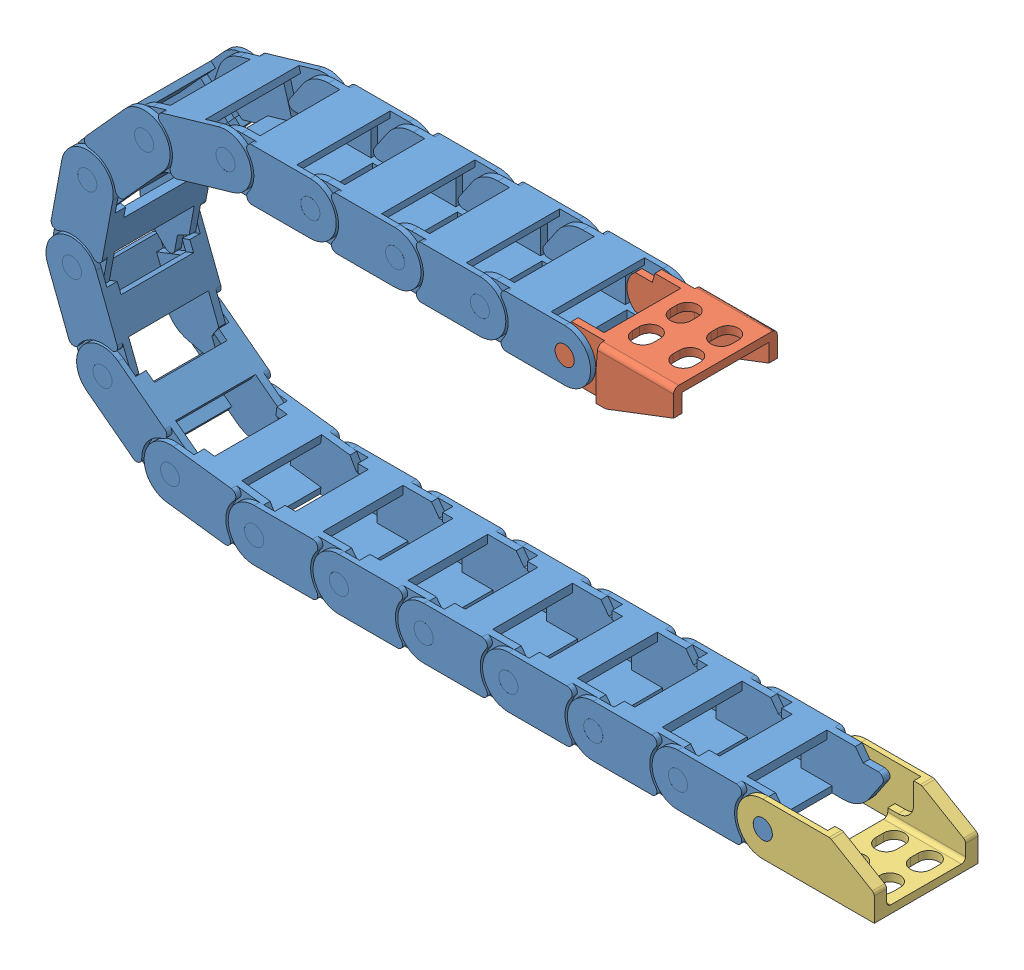
SolidWorks assembly CableCarrier, configuration Cable Carrier. Lengths in mm.
Overall size (586.32 71.86 20).
19 component instances, 4 part files, 8 mates.
Components (placement in the parent):
- trace_line^CableCarrier-1: trace_line^CableCarrier [По умолчанию] at (346.833 0 0) x (-1 0 0) z (0 0 1) size (586.32 60 0) (virtual)
- CableChainSection-7: CableChainSection [Cable Chain Section] at (-95.0099 -5 0) size (26.9 10 20)
- CableChainSection-8: CableChainSection [Cable Chain Section] at (-111.3599 -5 0) size (26.9 10 20)
- CableChainSection-9: CableChainSection [Cable Chain Section] at (-127.7099 -5 0) size (26.9 10 20)
- CableChainSection-10: CableChainSection [Cable Chain Section] at (-144.0597 -5.0003 0) x (1 0.000043 0) z (0 0 1) size (26.9 10 20)
- CableChainSection-11: CableChainSection [Cable Chain Section] at (-158.7278 -6.7623 0) x (0.959914 0.280294 0) z (0 0 1) size (26.9 10 20)
- CableChainSection-12: CableChainSection [Cable Chain Section] at (-170.0872 -13.1295 0) x (0.670389 0.74201 0) z (0 0 1) size (26.9 10 20)
- CableChainSection-13: CableChainSection [Cable Chain Section] at (-176.4208 -24.5075 0) x (0.181736 0.983347 0) z (0 0 1) size (26.9 10 20)
- CableChainSection-14: CableChainSection [Cable Chain Section] at (-175.8474 -37.5169 0) x (-0.360896 0.932606 0) z (0 0 1) size (26.9 10 20)
- CableChainSection-15: CableChainSection [Cable Chain Section] at (-168.5375 -48.2935 0) x (-0.796334 0.604857 0) z (0 0 1) size (26.9 10 20)
- CableChainSection-16: CableChainSection [Cable Chain Section] at (-156.5395 -53.8568 0) x (-0.991958 0.126567 0) z (0 0 1) size (26.9 10 20)
- CableChainSection-17: CableChainSection [Cable Chain Section] at (-140.8975 -55 0) x (-1 0 0) z (0 0 1) size (26.9 10 20)
- CarrierPartMale-2: CarrierPartMale [Carrier Part Male] at (-75.0099 5 0) x (0 0 1) z (1 0 0) size (20 10 26.4)
- CarrierPartFemale-1: CarrierPartFemale [Carrier Part Female] at (-35.7975 -63.5 0) x (0 0 1) z (0 -1 0) size (20 26.5 10)
- CableChainSection-18: CableChainSection [Cable Chain Section] at (-124.5475 -55 0) x (-1 0 0) z (0 0 1) size (26.9 10 20)
- CableChainSection-19: CableChainSection [Cable Chain Section] at (-108.1975 -55 0) x (-1 0 0) z (0 0 1) size (26.9 10 20)
- CableChainSection-20: CableChainSection [Cable Chain Section] at (-91.8475 -55 0) x (-1 0 0) z (0 0 1) size (26.9 10 20)
- CableChainSection-21: CableChainSection [Cable Chain Section] at (-75.4975 -55 0) x (-1 0 0) z (0 0 1) size (26.9 10 20)
- CableChainSection-22: CableChainSection [Cable Chain Section] at (-59.1475 -55 0) x (-1 0 0) z (0 0 1) size (26.9 10 20)
Mates (geometry in assembly coordinates):
- Coincident8: coincident aligned: plane of trace_line-1 through (346.833 0 0) normal (0 0 1); plane of assembly through (0 0 0) normal (0 0 1)
- Coincident9: coincident anti-aligned: plane of trace_line-1 through (346.833 0 0) normal (0 -1 0); plane of assembly through (0 0 0) normal (0 1 0)
- Coincident10: coincident aligned: plane of CableChainSection-7 through (-95.0099 0 0) normal (0 1 0); plane of assembly through (0 0 0) normal (0 1 0)
- Coincident11: coincident aligned: plane of CableChainSection-7 through (-95.0099 -5 0) normal (0 0 1); plane of assembly through (0 0 0) normal (0 0 1)
- Coincident12: coincident aligned: plane of CableChainSection-7 through (-95.0099 -5 0) normal (0 0 1); plane of Edge2-2 through (-75.0099 5 0) normal (0 0 1)
- Concentric2: concentric aligned: cylinder of CableChainSection-7 through (-88.0099 0 9) axis (0 0 1) radius 1.85; cylinder of Edge2-2 through (-88.0099 0 8.7) axis (0 0 1) radius 1.85
- Coincident13: coincident aligned: plane of Edge1-1 through (-35.7975 -63.5 0) normal (0 0 1); plane of assembly through (0 0 0) normal (0 0 1)
- Concentric6: concentric anti-aligned: cylinder of Edge1-1 through (-49.7975 -60 7.6) axis (0 0 1) radius 1.85; cylinder of CableChainSection-22 through (-49.7975 -60 10) axis (0 0 -1) radius 1.85
